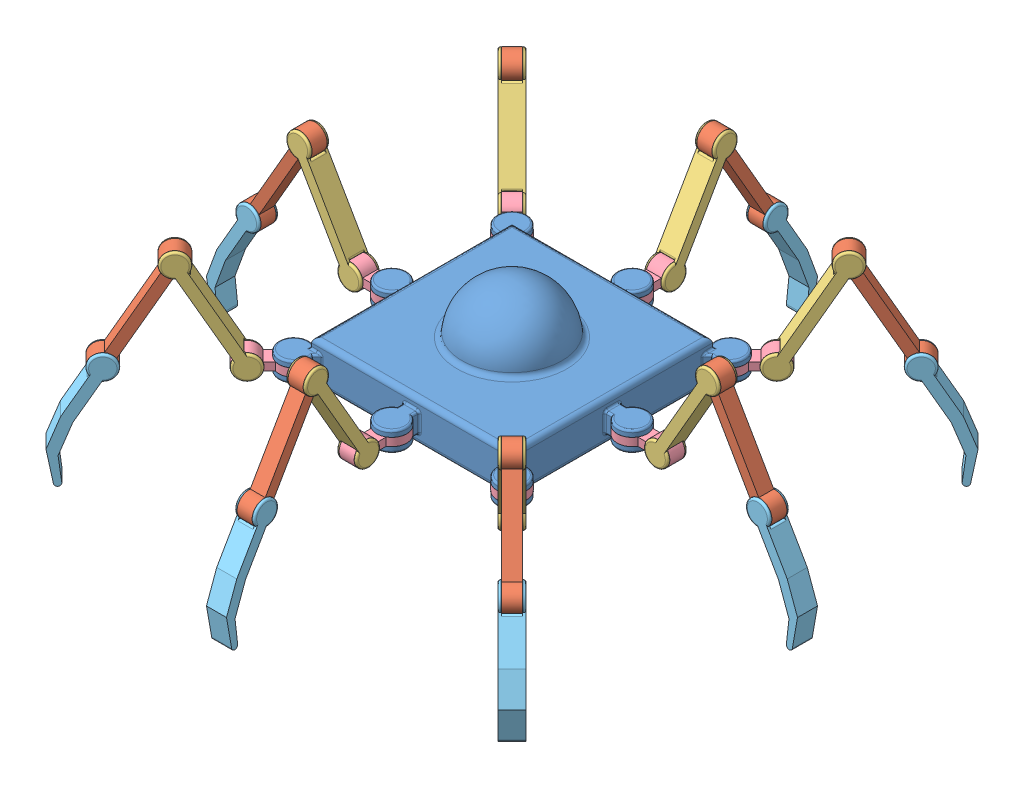
SolidWorks assembly SpiderBot_6Legs, configuration Default. Lengths in mm.
Overall size (634.89 234.57 634.89).
33 component instances, 5 part files, 146 mates.
Components (placement in the parent):
- spider_body-1: spider_body [Default] at (0 150 0) x (0 0 -1) z (0 -1 0) size (270 270 90)
- Link_C-24: Link_C [Default] at (-183.9152 176.5882 -194.5218) x (0.353553 0.866025 0.353553) z (-0.707107 0 0.707107) size (125.82 24 15)
- Link_B-24: Link_B [Default] at (-140.0258 176.5882 -154.1679) x (-0.707107 0 0.707107) z (-0.353553 0.866025 -0.353553) size (20.32 24 125.82)
- Link_A-24: Link_A [Default] at (-108.832 134 -108.832) x (-0.707107 0 -0.707107) z (0 -1 0) size (59.99 30 24)
- Link_D-24: Link_D [Default] at (-232.2874 88.4118 -218.1453) x (0.707107 0 -0.707107) z (0.353553 0.866025 0.353553) size (20.32 36.78 116.49)
- Link_C-26: Link_C [Default] at (-194.5218 176.5882 183.9152) x (0.353553 0.866025 -0.353553) z (0.707107 0 0.707107) size (125.82 24 15)
- Link_B-26: Link_B [Default] at (-154.1679 176.5882 140.0258) x (0.707107 0 0.707107) z (-0.353553 0.866025 0.353553) size (20.32 24 125.82)
- Link_A-26: Link_A [Default] at (-108.832 134 108.832) x (-0.707107 0 0.707107) z (0 -1 0) size (59.99 30 24)
- Link_D-26: Link_D [Default] at (-218.1453 88.4118 232.2874) x (-0.707107 0 -0.707107) z (0.353553 0.866025 -0.353553) size (20.32 36.78 116.49)
- Link_C-27: Link_C [Default] at (183.9152 176.5882 194.5218) x (-0.353553 0.866025 -0.353553) z (0.707107 0 -0.707107) size (125.82 24 15)
- Link_B-27: Link_B [Default] at (140.0258 176.5882 154.1679) x (0.707107 0 -0.707107) z (0.353553 0.866025 0.353553) size (20.32 24 125.82)
- Link_A-27: Link_A [Default] at (108.832 134 108.832) x (0.707107 0 0.707107) z (0 -1 0) size (59.99 30 24)
- Link_D-27: Link_D [Default] at (232.2874 88.4118 218.1453) x (-0.707107 0 0.707107) z (-0.353553 0.866025 -0.353553) size (20.32 36.78 116.49)
- Link_B-33: Link_B [Default] at (154.1679 176.5882 -140.0258) x (-0.707107 0 -0.707107) z (0.353553 0.866025 -0.353553) size (20.32 24 125.82)
- Link_D-31: Link_D [Default] at (218.1453 88.4118 -232.2874) x (0.707107 0 0.707107) z (-0.353553 0.866025 0.353553) size (20.32 36.78 116.49)
- Link_A-31: Link_A [Default] at (108.832 134 -108.832) x (0.707107 0 -0.707107) z (0 -1 0) size (59.99 30 24)
- Link_C-31: Link_C [Default] at (194.5218 176.5882 -183.9152) x (-0.353553 0.866025 0.353553) z (-0.707107 0 -0.707107) size (125.82 24 15)
- Link_D-34: Link_D [Default] at (-284.5923 88.4118 10) x (0 0 -1) z (0.5 0.866025 0) size (20.32 36.78 116.49)
- Link_A-34: Link_A [Default] at (-120 134 0) x (-1 0 0) z (0 -1 0) size (59.99 30 24)
- Link_B-36: Link_B [Default] at (-174.1146 176.5882 -10) x (0 0 1) z (-0.5 0.866025 0) size (20.32 24 125.82)
- Link_C-34: Link_C [Default] at (-233.6836 176.5882 -7.5) x (0.5 0.866025 0) z (0 0 1) size (125.82 24 15)
- Link_A-35: Link_A [Default] at (120 134 0) x (1 0 0) z (0 -1 0) size (59.99 30 24)
- Link_D-35: Link_D [Default] at (284.5923 88.4118 -10) x (0 0 1) z (-0.5 0.866025 0) size (20.32 36.78 116.49)
- Link_C-35: Link_C [Default] at (233.6836 176.5882 7.5) x (-0.5 0.866025 0) z (0 0 -1) size (125.82 24 15)
- Link_B-37: Link_B [Default] at (174.1146 176.5882 10) x (0 0 -1) z (0.5 0.866025 0) size (20.32 24 125.82)
- Link_A-36: Link_A [Default] at (0 134 120) x (0 0 1) z (0 -1 0) size (59.99 30 24)
- Link_D-36: Link_D [Default] at (10 88.4118 284.5923) x (-1 0 0) z (0 0.866025 -0.5) size (20.32 36.78 116.49)
- Link_C-36: Link_C [Default] at (-7.5 176.5882 233.6836) x (0 0.866025 -0.5) z (1 0 0) size (125.82 24 15)
- Link_B-38: Link_B [Default] at (-10 176.5882 174.1146) x (1 0 0) z (0 0.866025 0.5) size (20.32 24 125.82)
- Link_A-37: Link_A [Default] at (0 134 -120) x (0 0 -1) z (0 -1 0) size (59.99 30 24)
- Link_D-37: Link_D [Default] at (-10 88.4118 -284.5923) x (1 0 0) z (0 0.866025 0.5) size (20.32 36.78 116.49)
- Link_C-37: Link_C [Default] at (7.5 176.5882 -233.6836) x (0 0.866025 0.5) z (-1 0 0) size (125.82 24 15)
- Link_B-39: Link_B [Default] at (10 176.5882 -174.1146) x (-1 0 0) z (0 0.866025 -0.5) size (20.32 24 125.82)
Mates (geometry in assembly coordinates):
- Coincident4: coincident anti-aligned: plane of Link_B-2 through (235.0341 -365.5738 720.8033) normal (-1 0 0); plane of Link_C-2 through (235.0341 -453.7502 771.712) normal (1 0 0)
- Concentric4: concentric anti-aligned: cylinder of Link_B-2 through (220.0341 -365.5738 720.8033) axis (1 0 0) radius 4; cylinder of Link_C-2 through (235.0341 -365.5738 720.8033) axis (-1 0 0) radius 4
- Coincident5: coincident anti-aligned: plane of Link_C-2 through (235.0341 -453.7502 771.712) normal (1 0 0); plane of Link_D-2 through (235.0341 -453.7502 771.712) normal (-1 0 0)
- Concentric6: concentric aligned: cylinder of Link_C-2 through (235.0341 -453.7502 771.712) axis (-1 0 0) radius 4; cylinder of Link_D-2 through (235.0341 -453.7502 771.712) axis (-1 0 0) radius 4
- Coincident7: coincident anti-aligned: plane of Link_B-3 through (281.248 -759.0313 934.2797) normal (-1 0 0); plane of Link_C-3 through (281.248 -847.2078 985.1885) normal (1 0 0)
- Concentric7: concentric anti-aligned: cylinder of Link_B-3 through (266.248 -759.0313 934.2797) axis (1 0 0) radius 4; cylinder of Link_C-3 through (281.248 -759.0313 934.2797) axis (-1 0 0) radius 4
- Coincident8: coincident anti-aligned: plane of Link_C-3 through (281.248 -847.2078 985.1885) normal (1 0 0); plane of Link_D-3 through (281.248 -847.2078 985.1885) normal (-1 0 0)
- Concentric9: concentric aligned: cylinder of Link_C-3 through (281.248 -847.2078 985.1885) axis (-1 0 0) radius 4; cylinder of Link_D-3 through (281.248 -847.2078 985.1885) axis (-1 0 0) radius 4
- Coincident10: coincident anti-aligned: plane of Link_B-4 through (178.5336 -465.5708 822.703) normal (-1 0 0); plane of Link_C-4 through (178.5336 -553.7473 873.6117) normal (1 0 0)
- Concentric10: concentric anti-aligned: cylinder of Link_B-4 through (163.5336 -465.5708 822.703) axis (1 0 0) radius 4; cylinder of Link_C-4 through (178.5336 -465.5708 822.703) axis (-1 0 0) radius 4
- Coincident11: coincident anti-aligned: plane of Link_C-4 through (178.5336 -553.7473 873.6117) normal (1 0 0); plane of Link_D-4 through (178.5336 -553.7473 873.6117) normal (-1 0 0)
- Concentric12: concentric aligned: cylinder of Link_C-4 through (178.5336 -553.7473 873.6117) axis (-1 0 0) radius 4; cylinder of Link_D-4 through (178.5336 -553.7473 873.6117) axis (-1 0 0) radius 4
- Coincident13: coincident anti-aligned: plane of Link_B-5 through (262.376 -1013.0932 1106.1332) normal (-1 0 0); plane of Link_C-5 through (262.376 -1101.2696 1157.0419) normal (1 0 0)
- Concentric13: concentric anti-aligned: cylinder of Link_B-5 through (247.376 -1013.0932 1106.1332) axis (1 0 0) radius 4; cylinder of Link_C-5 through (262.376 -1013.0932 1106.1332) axis (-1 0 0) radius 4
- Coincident14: coincident anti-aligned: plane of Link_C-5 through (262.376 -1101.2696 1157.0419) normal (1 0 0); plane of Link_D-5 through (262.376 -1101.2696 1157.0419) normal (-1 0 0)
- Concentric15: concentric aligned: cylinder of Link_C-5 through (262.376 -1101.2696 1157.0419) axis (-1 0 0) radius 4; cylinder of Link_D-5 through (262.376 -1101.2696 1157.0419) axis (-1 0 0) radius 4
- Coincident16: coincident anti-aligned: plane of Link_B-6 through (534.9738 -1642.7072 1309.0583) normal (-1 0 0); plane of Link_C-6 through (534.9738 -1730.8837 1359.9671) normal (1 0 0)
- Concentric16: concentric anti-aligned: cylinder of Link_B-6 through (519.9738 -1642.7072 1309.0583) axis (1 0 0) radius 4; cylinder of Link_C-6 through (534.9738 -1642.7072 1309.0583) axis (-1 0 0) radius 4
- Coincident17: coincident anti-aligned: plane of Link_C-6 through (534.9738 -1730.8837 1359.9671) normal (1 0 0); plane of Link_D-6 through (534.9738 -1730.8837 1359.9671) normal (-1 0 0)
- Concentric18: concentric aligned: cylinder of Link_C-6 through (534.9738 -1730.8837 1359.9671) axis (-1 0 0) radius 4; cylinder of Link_D-6 through (534.9738 -1730.8837 1359.9671) axis (-1 0 0) radius 4
- Coincident19: coincident anti-aligned: plane of Link_B-7 through (-306.3909 -269.9837 1039.0888) normal (-1 0 0); plane of Link_C-7 through (-306.3909 -358.1602 1089.9975) normal (1 0 0)
- Concentric19: concentric anti-aligned: cylinder of Link_B-7 through (-321.3909 -269.9837 1039.0888) axis (1 0 0) radius 4; cylinder of Link_C-7 through (-306.3909 -269.9837 1039.0888) axis (-1 0 0) radius 4
- Coincident20: coincident anti-aligned: plane of Link_C-7 through (-306.3909 -358.1602 1089.9975) normal (1 0 0); plane of Link_D-7 through (-306.3909 -358.1602 1089.9975) normal (-1 0 0)
- Concentric21: concentric aligned: cylinder of Link_C-7 through (-306.3909 -358.1602 1089.9975) axis (-1 0 0) radius 4; cylinder of Link_D-7 through (-306.3909 -358.1602 1089.9975) axis (-1 0 0) radius 4
- Coincident22: coincident anti-aligned: plane of Link_B-8 through (-311.8852 -488.0983 1179.1514) normal (-1 0 0); plane of Link_C-8 through (-311.8852 -576.2747 1230.0601) normal (1 0 0)
- Concentric22: concentric anti-aligned: cylinder of Link_B-8 through (-326.8852 -488.0983 1179.1514) axis (1 0 0) radius 4; cylinder of Link_C-8 through (-311.8852 -488.0983 1179.1514) axis (-1 0 0) radius 4
- Coincident23: coincident anti-aligned: plane of Link_C-8 through (-311.8852 -576.2747 1230.0601) normal (1 0 0); plane of Link_D-8 through (-311.8852 -576.2747 1230.0601) normal (-1 0 0)
- Concentric24: concentric aligned: cylinder of Link_C-8 through (-311.8852 -576.2747 1230.0601) axis (-1 0 0) radius 4; cylinder of Link_D-8 through (-311.8852 -576.2747 1230.0601) axis (-1 0 0) radius 4
- Coincident25: coincident anti-aligned: plane of Link_B-9 through (-611.4857 -390.9688 1327.6493) normal (-1 0 0); plane of Link_C-9 through (-611.4857 -479.1453 1378.558) normal (1 0 0)
- Concentric25: concentric anti-aligned: cylinder of Link_B-9 through (-626.4857 -390.9688 1327.6493) axis (1 0 0) radius 4; cylinder of Link_C-9 through (-611.4857 -390.9688 1327.6493) axis (-1 0 0) radius 4
- Coincident26: coincident anti-aligned: plane of Link_C-9 through (-611.4857 -479.1453 1378.558) normal (1 0 0); plane of Link_D-9 through (-611.4857 -479.1453 1378.558) normal (-1 0 0)
- Concentric27: concentric aligned: cylinder of Link_C-9 through (-611.4857 -479.1453 1378.558) axis (-1 0 0) radius 4; cylinder of Link_D-9 through (-611.4857 -479.1453 1378.558) axis (-1 0 0) radius 4
- Coincident28: coincident anti-aligned: plane of Link_B-10 through (-139.42 -657.5126 1164.5577) normal (-1 0 0); plane of Link_C-10 through (-139.42 -745.689 1215.4664) normal (1 0 0)
- Concentric28: concentric anti-aligned: cylinder of Link_B-10 through (-154.42 -657.5126 1164.5577) axis (1 0 0) radius 4; cylinder of Link_C-10 through (-139.42 -657.5126 1164.5577) axis (-1 0 0) radius 4
- Coincident29: coincident anti-aligned: plane of Link_C-10 through (-139.42 -745.689 1215.4664) normal (1 0 0); plane of Link_D-10 through (-139.42 -745.689 1215.4664) normal (-1 0 0)
- Concentric30: concentric aligned: cylinder of Link_C-10 through (-139.42 -745.689 1215.4664) axis (-1 0 0) radius 4; cylinder of Link_D-10 through (-139.42 -745.689 1215.4664) axis (-1 0 0) radius 4
- Coincident31: coincident anti-aligned: plane of Link_B-11 through (-139.42 -657.5126 1164.5577) normal (-1 0 0); plane of Link_C-11 through (-139.42 -745.689 1215.4664) normal (1 0 0)
- Concentric31: concentric anti-aligned: cylinder of Link_B-11 through (-154.42 -657.5126 1164.5577) axis (1 0 0) radius 4; cylinder of Link_C-11 through (-139.42 -657.5126 1164.5577) axis (-1 0 0) radius 4
- Coincident32: coincident anti-aligned: plane of Link_C-11 through (-139.42 -745.689 1215.4664) normal (1 0 0); plane of Link_D-11 through (-139.42 -745.689 1215.4664) normal (-1 0 0)
- Concentric33: concentric aligned: cylinder of Link_C-11 through (-139.42 -745.689 1215.4664) axis (-1 0 0) radius 4; cylinder of Link_D-11 through (-139.42 -745.689 1215.4664) axis (-1 0 0) radius 4
- Coincident34: coincident anti-aligned: plane of Link_B-12 through (-94.7509 -804.43 1225.1322) normal (-1 0 0); plane of Link_C-12 through (-94.7509 -892.6065 1276.0409) normal (1 0 0)
- Concentric34: concentric anti-aligned: cylinder of Link_B-12 through (-109.7509 -804.43 1225.1322) axis (1 0 0) radius 4; cylinder of Link_C-12 through (-94.7509 -804.43 1225.1322) axis (-1 0 0) radius 4
- Coincident35: coincident anti-aligned: plane of Link_C-12 through (-94.7509 -892.6065 1276.0409) normal (1 0 0); plane of Link_D-12 through (-94.7509 -892.6065 1276.0409) normal (-1 0 0)
- Concentric36: concentric aligned: cylinder of Link_C-12 through (-94.7509 -892.6065 1276.0409) axis (-1 0 0) radius 4; cylinder of Link_D-12 through (-94.7509 -892.6065 1276.0409) axis (-1 0 0) radius 4
- Concentric78: concentric anti-aligned: cylinder of Link_C-24 through (-173.461 218.1765 -162.8544) axis (0.707107 0 -0.707107) radius 4; cylinder of Link_B-24 through (-162.8544 218.1765 -173.461) axis (-0.707107 0 0.707107) radius 4
- Concentric79: concentric anti-aligned: cylinder of Link_B-24 through (-126.8565 130 -137.4631) axis (-0.707107 0 0.707107) radius 4; cylinder of Link_A-24 through (-142.7664 130 -121.5532) axis (0.707107 0 -0.707107) radius 5
- Coincident86: coincident anti-aligned: plane of Link_B-24 through (-137.4631 130 -126.8565) normal (0.707107 0 -0.707107); plane of Link_A-24 through (-123.3209 126 -112.7143) normal (-0.707107 0 0.707107)
- Coincident87: coincident anti-aligned: plane of Link_C-24 through (-198.8522 130 -209.4588) normal (0.707107 0 -0.707107); plane of Link_B-24 through (-162.8544 218.1765 -173.461) normal (-0.707107 0 0.707107)
- Coincident88: coincident anti-aligned: plane of Link_C-24 through (-209.4588 130 -198.8522) normal (-0.707107 0 0.707107); plane of Link_B-24 through (-173.461 218.1765 -162.8544) normal (0.707107 0 -0.707107)
- Coincident89: coincident anti-aligned: plane of Link_C-24 through (-198.8522 130 -209.4588) normal (0.707107 0 -0.707107); plane of Link_D-24 through (-198.8522 130 -209.4588) normal (-0.707107 0 0.707107)
- Concentric80: concentric aligned: cylinder of Link_C-24 through (-209.4588 130 -198.8522) axis (0.707107 0 -0.707107) radius 4; cylinder of Link_D-24 through (-209.4588 130 -198.8522) axis (0.707107 0 -0.707107) radius 4
- Coincident90: coincident anti-aligned: plane of Link_B-24 through (-126.8565 130 -137.4631) normal (-0.707107 0 0.707107); plane of Link_A-24 through (-112.7143 126 -123.3209) normal (0.707107 0 -0.707107)
- Coincident91: coincident anti-aligned: plane of Link_C-24 through (-209.4588 130 -198.8522) normal (-0.707107 0 0.707107); plane of Link_D-24 through (-209.4588 130 -198.8522) normal (0.707107 0 -0.707107)
- Concentric84: concentric anti-aligned: cylinder of Link_C-26 through (-162.8544 218.1765 173.461) axis (-0.707107 0 -0.707107) radius 4; cylinder of Link_B-26 through (-173.461 218.1765 162.8544) axis (0.707107 0 0.707107) radius 4
- Concentric85: concentric anti-aligned: cylinder of Link_B-26 through (-137.4631 130 126.8565) axis (0.707107 0 0.707107) radius 4; cylinder of Link_A-26 through (-121.5532 130 142.7664) axis (-0.707107 0 -0.707107) radius 5
- Coincident98: coincident anti-aligned: plane of Link_B-26 through (-126.8565 130 137.4631) normal (-0.707107 0 -0.707107); plane of Link_A-26 through (-112.7143 126 123.3209) normal (0.707107 0 0.707107)
- Coincident99: coincident anti-aligned: plane of Link_C-26 through (-209.4588 130 198.8522) normal (-0.707107 0 -0.707107); plane of Link_B-26 through (-173.461 218.1765 162.8544) normal (0.707107 0 0.707107)
- Coincident100: coincident anti-aligned: plane of Link_C-26 through (-198.8522 130 209.4588) normal (0.707107 0 0.707107); plane of Link_B-26 through (-162.8544 218.1765 173.461) normal (-0.707107 0 -0.707107)
- Coincident101: coincident anti-aligned: plane of Link_C-26 through (-209.4588 130 198.8522) normal (-0.707107 0 -0.707107); plane of Link_D-26 through (-209.4588 130 198.8522) normal (0.707107 0 0.707107)
- Concentric86: concentric aligned: cylinder of Link_C-26 through (-198.8522 130 209.4588) axis (-0.707107 0 -0.707107) radius 4; cylinder of Link_D-26 through (-198.8522 130 209.4588) axis (-0.707107 0 -0.707107) radius 4
- Coincident102: coincident anti-aligned: plane of Link_B-26 through (-137.4631 130 126.8565) normal (0.707107 0 0.707107); plane of Link_A-26 through (-123.3209 126 112.7143) normal (-0.707107 0 -0.707107)
- Coincident103: coincident anti-aligned: plane of Link_C-26 through (-198.8522 130 209.4588) normal (0.707107 0 0.707107); plane of Link_D-26 through (-198.8522 130 209.4588) normal (-0.707107 0 -0.707107)
- Concentric87: concentric anti-aligned: cylinder of Link_C-27 through (173.461 218.1765 162.8544) axis (-0.707107 0 0.707107) radius 4; cylinder of Link_B-27 through (162.8544 218.1765 173.461) axis (0.707107 0 -0.707107) radius 4
- Concentric88: concentric anti-aligned: cylinder of Link_B-27 through (126.8565 130 137.4631) axis (0.707107 0 -0.707107) radius 4; cylinder of Link_A-27 through (142.7664 130 121.5532) axis (-0.707107 0 0.707107) radius 5
- Coincident104: coincident anti-aligned: plane of Link_B-27 through (137.4631 130 126.8565) normal (-0.707107 0 0.707107); plane of Link_A-27 through (123.3209 126 112.7143) normal (0.707107 0 -0.707107)
- Coincident105: coincident anti-aligned: plane of Link_C-27 through (198.8522 130 209.4588) normal (-0.707107 0 0.707107); plane of Link_B-27 through (162.8544 218.1765 173.461) normal (0.707107 0 -0.707107)
- Coincident106: coincident anti-aligned: plane of Link_C-27 through (209.4588 130 198.8522) normal (0.707107 0 -0.707107); plane of Link_B-27 through (173.461 218.1765 162.8544) normal (-0.707107 0 0.707107)
- Coincident107: coincident anti-aligned: plane of Link_C-27 through (198.8522 130 209.4588) normal (-0.707107 0 0.707107); plane of Link_D-27 through (198.8522 130 209.4588) normal (0.707107 0 -0.707107)
- Concentric89: concentric aligned: cylinder of Link_C-27 through (209.4588 130 198.8522) axis (-0.707107 0 0.707107) radius 4; cylinder of Link_D-27 through (209.4588 130 198.8522) axis (-0.707107 0 0.707107) radius 4
- Coincident108: coincident anti-aligned: plane of Link_B-27 through (126.8565 130 137.4631) normal (0.707107 0 -0.707107); plane of Link_A-27 through (112.7143 126 123.3209) normal (-0.707107 0 0.707107)
- Coincident109: coincident anti-aligned: plane of Link_C-27 through (209.4588 130 198.8522) normal (0.707107 0 -0.707107); plane of Link_D-27 through (209.4588 130 198.8522) normal (-0.707107 0 0.707107)
- Coincident124: coincident anti-aligned: plane of spider_body-1 through (108.832 134 108.832) normal (0 -1 0); plane of Link_A-27 through (108.832 134 108.832) normal (0 1 0)
- Coincident125: coincident anti-aligned: plane of spider_body-1 through (108.832 126 108.832) normal (0 1 0); plane of Link_A-27 through (108.832 126 108.832) normal (0 -1 0)
- Concentric97: concentric anti-aligned: cylinder of spider_body-1 through (108.832 134 108.832) axis (0 -1 0) radius 10; cylinder of Link_A-27 through (108.832 126 108.832) axis (0 1 0) radius 10
- Coincident126: coincident anti-aligned: plane of spider_body-1 through (-108.832 134 108.832) normal (0 -1 0); plane of Link_A-26 through (-108.832 134 108.832) normal (0 1 0)
- Coincident127: coincident anti-aligned: plane of spider_body-1 through (-108.832 126 108.832) normal (0 1 0); plane of Link_A-26 through (-108.832 126 108.832) normal (0 -1 0)
- Concentric98: concentric anti-aligned: cylinder of spider_body-1 through (-108.832 134 108.832) axis (0 -1 0) radius 10; cylinder of Link_A-26 through (-108.832 126 108.832) axis (0 1 0) radius 10
- Coincident138: coincident anti-aligned: plane of Link_B-33 through (162.8544 218.1765 -173.461) normal (0.707107 0 0.707107); plane of Link_C-31 through (198.8522 130 -209.4588) normal (-0.707107 0 -0.707107)
- Coincident139: coincident anti-aligned: plane of Link_D-31 through (209.4588 130 -198.8522) normal (-0.707107 0 -0.707107); plane of Link_C-31 through (209.4588 130 -198.8522) normal (0.707107 0 0.707107)
- Coincident140: coincident anti-aligned: plane of Link_D-31 through (198.8522 130 -209.4588) normal (0.707107 0 0.707107); plane of Link_C-31 through (198.8522 130 -209.4588) normal (-0.707107 0 -0.707107)
- Concentric104: concentric aligned: cylinder of Link_D-31 through (198.8522 130 -209.4588) axis (0.707107 0 0.707107) radius 4; cylinder of Link_C-31 through (198.8522 130 -209.4588) axis (0.707107 0 0.707107) radius 4
- Coincident141: coincident anti-aligned: plane of Link_B-33 through (137.4631 130 -126.8565) normal (-0.707107 0 -0.707107); plane of Link_A-31 through (123.3209 126 -112.7143) normal (0.707107 0 0.707107)
- Concentric105: concentric anti-aligned: cylinder of Link_B-33 through (173.461 218.1765 -162.8544) axis (-0.707107 0 -0.707107) radius 4; cylinder of Link_C-31 through (162.8544 218.1765 -173.461) axis (0.707107 0 0.707107) radius 4
- Concentric106: concentric anti-aligned: cylinder of Link_B-33 through (137.4631 130 -126.8565) axis (-0.707107 0 -0.707107) radius 4; cylinder of Link_A-31 through (121.5532 130 -142.7664) axis (0.707107 0 0.707107) radius 5
- Coincident142: coincident anti-aligned: plane of Link_B-33 through (126.8565 130 -137.4631) normal (0.707107 0 0.707107); plane of Link_A-31 through (112.7143 126 -123.3209) normal (-0.707107 0 -0.707107)
- Coincident143: coincident anti-aligned: plane of Link_B-33 through (173.461 218.1765 -162.8544) normal (-0.707107 0 -0.707107); plane of Link_C-31 through (209.4588 130 -198.8522) normal (0.707107 0 0.707107)
- Coincident146: coincident anti-aligned: plane of spider_body-1 through (108.832 134 -108.832) normal (0 -1 0); plane of Link_A-31 through (108.832 134 -108.832) normal (0 1 0)
- Coincident147: coincident anti-aligned: plane of spider_body-1 through (108.832 126 -108.832) normal (0 1 0); plane of Link_A-31 through (108.832 126 -108.832) normal (0 -1 0)
- Concentric108: concentric anti-aligned: cylinder of spider_body-1 through (108.832 134 -108.832) axis (0 -1 0) radius 10; cylinder of Link_A-31 through (108.832 126 -108.832) axis (0 1 0) radius 10
- Coincident148: coincident anti-aligned: plane of spider_body-1 through (-108.832 134 -108.832) normal (0 -1 0); plane of Link_A-24 through (-108.832 134 -108.832) normal (0 1 0)
- Coincident149: coincident anti-aligned: plane of spider_body-1 through (-108.832 126 -108.832) normal (0 1 0); plane of Link_A-24 through (-108.832 126 -108.832) normal (0 -1 0)
- Concentric109: concentric anti-aligned: cylinder of spider_body-1 through (-108.832 134 -108.832) axis (0 -1 0) radius 10; cylinder of Link_A-24 through (-108.832 126 -108.832) axis (0 1 0) radius 10
- Concentric111: concentric anti-aligned: cylinder of Link_A-32 through (-1752.5654 2022.5976 -1745.769) axis (0.707107 0 -0.707107) radius 5; cylinder of Link_B-34 through (-1736.6555 2022.5976 -1761.6789) axis (-0.707107 0 0.707107) radius 4
- Coincident151: coincident anti-aligned: plane of Link_B-34 through (-1783.26 2110.774 -1787.0702) normal (0.707107 0 -0.707107); plane of Link_C-32 through (-1819.2579 2022.5976 -1823.0681) normal (-0.707107 0 0.707107)
- Concentric112: concentric anti-aligned: cylinder of Link_B-34 through (-1772.6534 2110.774 -1797.6768) axis (-0.707107 0 0.707107) radius 4; cylinder of Link_C-32 through (-1783.26 2110.774 -1787.0702) axis (0.707107 0 -0.707107) radius 4
- Coincident153: coincident anti-aligned: plane of Link_A-32 through (-1733.12 2018.5976 -1736.9302) normal (-0.707107 0 0.707107); plane of Link_B-34 through (-1747.2621 2022.5976 -1751.0723) normal (0.707107 0 -0.707107)
- Coincident154: coincident anti-aligned: plane of Link_B-34 through (-1772.6534 2110.774 -1797.6768) normal (-0.707107 0 0.707107); plane of Link_C-32 through (-1808.6513 2022.5976 -1833.6747) normal (0.707107 0 -0.707107)
- Coincident155: coincident anti-aligned: plane of Link_A-32 through (-1722.5134 2018.5976 -1747.5368) normal (0.707107 0 -0.707107); plane of Link_B-34 through (-1736.6555 2022.5976 -1761.6789) normal (-0.707107 0 0.707107)
- Concentric116: concentric aligned: cylinder of Link_D-34 through (-254.8078 130 7.5) axis (0 0 -1) radius 4; cylinder of Link_C-34 through (-254.8078 130 7.5) axis (0 0 -1) radius 4
- Coincident162: coincident anti-aligned: plane of Link_D-34 through (-254.8078 130 7.5) normal (0 0 -1); plane of Link_C-34 through (-254.8078 130 7.5) normal (0 0 1)
- Concentric117: concentric anti-aligned: cylinder of Link_A-34 through (-152.9904 130 15) axis (0 0 -1) radius 5; cylinder of Link_B-36 through (-152.9904 130 -7.5) axis (0 0 1) radius 4
- Coincident163: coincident anti-aligned: plane of Link_B-36 through (-203.8991 218.1765 7.5) normal (0 0 -1); plane of Link_C-34 through (-254.8078 130 7.5) normal (0 0 1)
- Concentric118: concentric anti-aligned: cylinder of Link_B-36 through (-203.8991 218.1765 -7.5) axis (0 0 1) radius 4; cylinder of Link_C-34 through (-203.8991 218.1765 7.5) axis (0 0 -1) radius 4
- Coincident164: coincident anti-aligned: plane of Link_D-34 through (-254.8078 130 -7.5) normal (0 0 1); plane of Link_C-34 through (-254.8078 130 -7.5) normal (0 0 -1)
- Coincident165: coincident anti-aligned: plane of Link_A-34 through (-132.9904 126 7.5) normal (0 0 1); plane of Link_B-36 through (-152.9904 130 7.5) normal (0 0 -1)
- Coincident166: coincident anti-aligned: plane of Link_B-36 through (-203.8991 218.1765 -7.5) normal (0 0 1); plane of Link_C-34 through (-254.8078 130 -7.5) normal (0 0 -1)
- Coincident167: coincident anti-aligned: plane of Link_A-34 through (-132.9904 126 -7.5) normal (0 0 -1); plane of Link_B-36 through (-152.9904 130 -7.5) normal (0 0 1)
- Concentric119: concentric aligned: cylinder of Link_D-35 through (254.8078 130 -7.5) axis (0 0 1) radius 4; cylinder of Link_C-35 through (254.8078 130 -7.5) axis (0 0 1) radius 4
- Concentric120: concentric anti-aligned: cylinder of Link_C-35 through (203.8991 218.1765 -7.5) axis (0 0 1) radius 4; cylinder of Link_B-37 through (203.8991 218.1765 7.5) axis (0 0 -1) radius 4
- Coincident168: coincident anti-aligned: plane of Link_A-35 through (132.9904 126 7.5) normal (0 0 1); plane of Link_B-37 through (152.9904 130 7.5) normal (0 0 -1)
- Coincident169: coincident anti-aligned: plane of Link_A-35 through (132.9904 126 -7.5) normal (0 0 -1); plane of Link_B-37 through (152.9904 130 -7.5) normal (0 0 1)
- Coincident170: coincident anti-aligned: plane of Link_D-35 through (254.8078 130 -7.5) normal (0 0 1); plane of Link_C-35 through (254.8078 130 -7.5) normal (0 0 -1)
- Concentric121: concentric anti-aligned: cylinder of Link_A-35 through (152.9904 130 -15) axis (0 0 1) radius 5; cylinder of Link_B-37 through (152.9904 130 7.5) axis (0 0 -1) radius 4
- Coincident171: coincident anti-aligned: plane of Link_C-35 through (254.8078 130 -7.5) normal (0 0 -1); plane of Link_B-37 through (203.8991 218.1765 -7.5) normal (0 0 1)
- Coincident172: coincident anti-aligned: plane of Link_D-35 through (254.8078 130 7.5) normal (0 0 -1); plane of Link_C-35 through (254.8078 130 7.5) normal (0 0 1)
- Coincident173: coincident anti-aligned: plane of Link_C-35 through (254.8078 130 7.5) normal (0 0 1); plane of Link_B-37 through (203.8991 218.1765 7.5) normal (0 0 -1)
- Concentric122: concentric aligned: cylinder of Link_D-36 through (7.5 130 254.8078) axis (-1 0 0) radius 4; cylinder of Link_C-36 through (7.5 130 254.8078) axis (-1 0 0) radius 4
- Concentric123: concentric anti-aligned: cylinder of Link_C-36 through (7.5 218.1765 203.8991) axis (-1 0 0) radius 4; cylinder of Link_B-38 through (-7.5 218.1765 203.8991) axis (1 0 0) radius 4
- Coincident174: coincident anti-aligned: plane of Link_A-36 through (-7.5 126 132.9904) normal (-1 0 0); plane of Link_B-38 through (-7.5 130 152.9904) normal (1 0 0)
- Coincident175: coincident anti-aligned: plane of Link_A-36 through (7.5 126 132.9904) normal (1 0 0); plane of Link_B-38 through (7.5 130 152.9904) normal (-1 0 0)
- Coincident176: coincident anti-aligned: plane of Link_D-36 through (7.5 130 254.8078) normal (-1 0 0); plane of Link_C-36 through (7.5 130 254.8078) normal (1 0 0)
- Concentric124: concentric anti-aligned: cylinder of Link_A-36 through (15 130 152.9904) axis (-1 0 0) radius 5; cylinder of Link_B-38 through (-7.5 130 152.9904) axis (1 0 0) radius 4
- Coincident177: coincident anti-aligned: plane of Link_C-36 through (7.5 130 254.8078) normal (1 0 0); plane of Link_B-38 through (7.5 218.1765 203.8991) normal (-1 0 0)
- Coincident178: coincident anti-aligned: plane of Link_D-36 through (-7.5 130 254.8078) normal (1 0 0); plane of Link_C-36 through (-7.5 130 254.8078) normal (-1 0 0)
- Coincident179: coincident anti-aligned: plane of Link_C-36 through (-7.5 130 254.8078) normal (-1 0 0); plane of Link_B-38 through (-7.5 218.1765 203.8991) normal (1 0 0)
- Concentric125: concentric aligned: cylinder of Link_D-37 through (-7.5 130 -254.8078) axis (1 0 0) radius 4; cylinder of Link_C-37 through (-7.5 130 -254.8078) axis (1 0 0) radius 4
- Concentric126: concentric anti-aligned: cylinder of Link_C-37 through (-7.5 218.1765 -203.8991) axis (1 0 0) radius 4; cylinder of Link_B-39 through (7.5 218.1765 -203.8991) axis (-1 0 0) radius 4
- Coincident180: coincident anti-aligned: plane of Link_A-37 through (7.5 126 -132.9904) normal (1 0 0); plane of Link_B-39 through (7.5 130 -152.9904) normal (-1 0 0)
- Coincident181: coincident anti-aligned: plane of Link_A-37 through (-7.5 126 -132.9904) normal (-1 0 0); plane of Link_B-39 through (-7.5 130 -152.9904) normal (1 0 0)
- Coincident182: coincident anti-aligned: plane of Link_D-37 through (-7.5 130 -254.8078) normal (1 0 0); plane of Link_C-37 through (-7.5 130 -254.8078) normal (-1 0 0)
- Concentric127: concentric anti-aligned: cylinder of Link_A-37 through (-15 130 -152.9904) axis (1 0 0) radius 5; cylinder of Link_B-39 through (7.5 130 -152.9904) axis (-1 0 0) radius 4
- Coincident183: coincident anti-aligned: plane of Link_C-37 through (-7.5 130 -254.8078) normal (-1 0 0); plane of Link_B-39 through (-7.5 218.1765 -203.8991) normal (1 0 0)
- Coincident184: coincident anti-aligned: plane of Link_D-37 through (7.5 130 -254.8078) normal (-1 0 0); plane of Link_C-37 through (7.5 130 -254.8078) normal (1 0 0)
- Coincident185: coincident anti-aligned: plane of Link_C-37 through (7.5 130 -254.8078) normal (1 0 0); plane of Link_B-39 through (7.5 218.1765 -203.8991) normal (-1 0 0)
- Coincident187: coincident anti-aligned: plane of spider_body-1 through (-120 134 0) normal (0 -1 0); plane of Link_A-34 through (-120 134 0) normal (0 1 0)
- Coincident188: coincident anti-aligned: plane of spider_body-1 through (-120 126 0) normal (0 1 0); plane of Link_A-34 through (-120 126 0) normal (0 -1 0)
- Concentric129: concentric anti-aligned: cylinder of spider_body-1 through (-120 134 0) axis (0 -1 0) radius 10; cylinder of Link_A-34 through (-120 126 0) axis (0 1 0) radius 10
- Coincident189: coincident anti-aligned: plane of spider_body-1 through (0 134 -120) normal (0 -1 0); plane of Link_A-37 through (0 134 -120) normal (0 1 0)
- Coincident190: coincident anti-aligned: plane of spider_body-1 through (0 126 -120) normal (0 1 0); plane of Link_A-37 through (0 126 -120) normal (0 -1 0)
- Concentric130: concentric anti-aligned: cylinder of spider_body-1 through (0 134 -120) axis (0 -1 0) radius 10; cylinder of Link_A-37 through (0 126 -120) axis (0 1 0) radius 10
- Coincident191: coincident anti-aligned: plane of spider_body-1 through (120 134 0) normal (0 -1 0); plane of Link_A-35 through (120 134 0) normal (0 1 0)
- Coincident192: coincident anti-aligned: plane of spider_body-1 through (120 126 0) normal (0 1 0); plane of Link_A-35 through (120 126 0) normal (0 -1 0)
- Concentric131: concentric anti-aligned: cylinder of spider_body-1 through (120 134 0) axis (0 -1 0) radius 10; cylinder of Link_A-35 through (120 126 0) axis (0 1 0) radius 10
- Coincident193: coincident anti-aligned: plane of spider_body-1 through (0 134 120) normal (0 -1 0); plane of Link_A-36 through (0 134 120) normal (0 1 0)
- Coincident194: coincident anti-aligned: plane of spider_body-1 through (0 126 120) normal (0 1 0); plane of Link_A-36 through (0 126 120) normal (0 -1 0)
- Concentric132: concentric anti-aligned: cylinder of spider_body-1 through (0 134 120) axis (0 -1 0) radius 10; cylinder of Link_A-36 through (0 126 120) axis (0 1 0) radius 10
